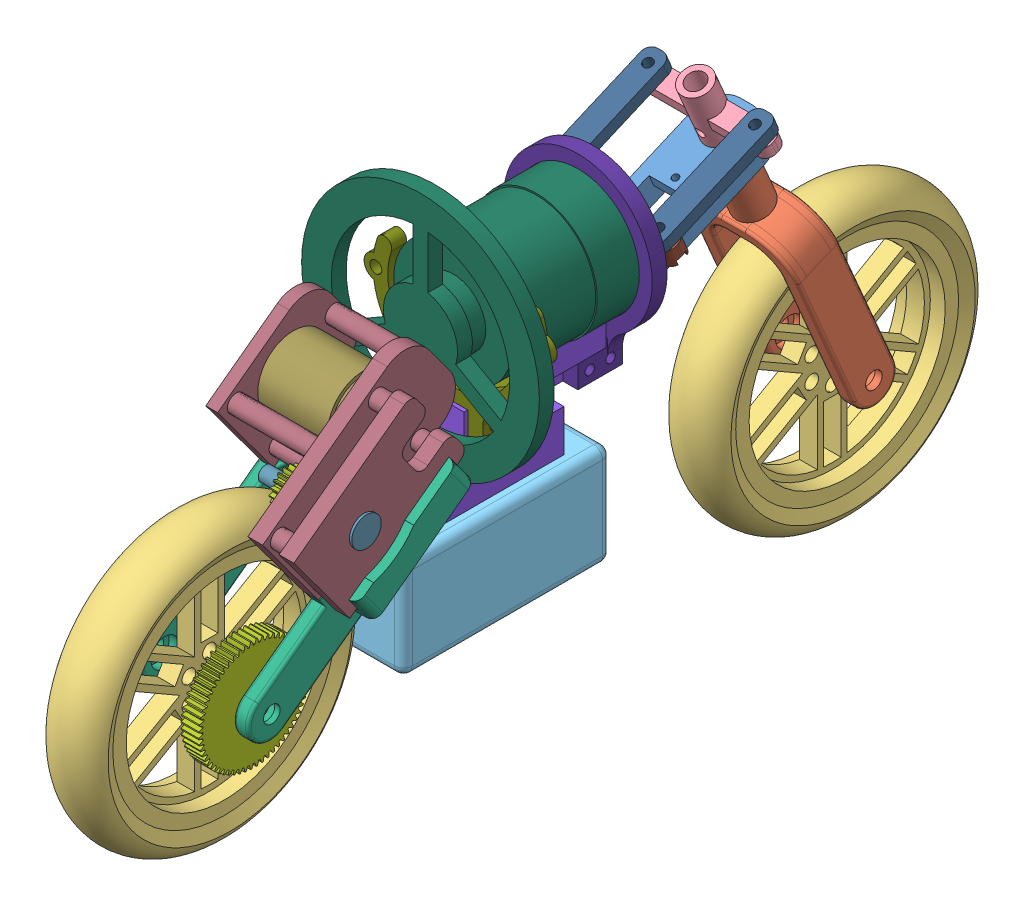
SolidWorks assembly assembly_v5.0, configuration 默认. Lengths in mm.
Overall size (81 161.31 304.62).
23 component instances, 18 part files, 54 mates.
Components (placement in the parent):
- fork_frame-1: fork_frame [默认] at (0 25.2643 106.3234) x (-1 0 0) z (0 0.394535 -0.918881) size (20 18.85 87.51)
- front_fork-1: front_fork [默认] at (0 3.2112 96.8545) x (1 0 0) z (0 -0.394535 0.918881) size (34 88 15)
- tire_v2-1: tire_v2 [默认] at (0 -51.9217 73.1825) x (0 0 -1) z (1 0 0) size (95 95 20)
- tire_v2-2: tire_v2 [默认] at (0 -40.9693 282.7998) x (0 0 -1) z (1 0 0) size (95 95 20)
- steer_link2-1: steer_link2 [默认] at (0 48.2363 116.1868) x (1 0 0) z (0 0.394535 -0.918881) size (45 20 10)
- battery-1: battery [默认] at (0 -50 190) x (0 0 1) z (-1 0 0) size (70 34 21)
- rear_fork_shift-1: rear_fork_shift [默认] at (0 -5.3014 234.5525) x (1 0 0) z (0 0.804121 0.594465) size (58 88.86 58.29)
- spur gear_gb-3: spur gear_gb [GB - Spur gear 0.6M 60T 20PA 6FW ---S60A75H50L5.0N] at (12 -40.9693 282.7998) size (6 37.17 37.17)
- main_body_v2-1: main_body_v2 [默认] at (0 -8.1106 154.2837) x (-1 0 0) z (0 0 -1) size (25 41 79.25)
- PCB-1: PCB [默认] at (-15 -40 189.1936) x (0 -1 0) z (0 0 -1) size (40 4 80)
- steer_link1-1: steer_link1 [默认] at (18 33.0029 128.8542) x (0 0.394535 -0.918881) z (1 0 0) size (44.22 4 7.76)
- steer_link1-2: steer_link1 [默认] at (-18 33.0029 128.8542) x (0 -0.394535 0.918881) z (-1 0 0) size (44.22 4 7.76)
- steer_link0-1: steer_link0 [默认] at (0 27.8147 140.9375) x (-1 0 0) z (0 -0.394535 0.918881) size (45 6 6.84)
- motor_assembly-1: motor_assembly [默认] at (-14.5712 50.6661 212.2557) x (1 0 0) z (0 -0.594465 0.804121) size (49.3 33.1 62.2)
  - motor-1: motor [默认] at (9.0712 0 42) x (1 0 0) z (0 -1 0) size (42 24 24)
  - motor_frame-1: motor_frame [默认] at (42.0712 0 53.1) x (-1 0 0) z (0 0 -1) size (47.5 33.1 62.2)
  - coupling-1: coupling [默认] at (48.3712 0 66.5) x (-1 0 0) z (0 -0.924225 -0.381849) size (34 10.2 13.1)
- 零件3^assembly_v5.0-1: 零件3^assembly_v5.0 [默认] at origin (virtual)
- spur gear_gb-4: spur gear_gb [GB - Spur gear 0.6M 18T 20PA 6FW ---S18A75H50L5.0N] at (12 11.1341 265.7298) size (6 11.87 12)
- flywheel-2: flywheel [默认] at (0 21.8894 149.7837) size (80 80 59)
  - flywheel-1: flywheel [默认] at origin size (80 80 59)
  - flywheel_holder1-1: flywheel_holder1 [默认] at (0 0 48) x (1 0 0) z (0 1 0) size (60 15 44.31)
  - flywheel_holder2-1: flywheel_holder2 [默认] at (0 0 1) x (-1 0 0) z (0 1 0) size (50 15 58.81)
Mates (geometry in assembly coordinates):
- 重合1: coincident: plane of ? through (0 -31.075 159.9884) normal (1 0 0); plane of assembly through (0 0 0) normal (1 0 0)
- 同心1: concentric: circle of ?; circle of ?
- 重合3: coincident anti-aligned: plane of fork_frame-1 through (0 25.2643 106.3234) normal (-1 0 0); plane of assembly through (0 0 0) normal (1 0 0)
- 重合6: coincident: plane of ? through (0 -10.6832 225.7266) normal (1 0 0); plane of assembly through (0 0 0) normal (1 0 0)
- 同心7: concentric aligned: circle of fork_frame-1; circle of front_fork-1
- 同心4: concentric: circle of ?; circle of ?
- 平行2: parallel: plane of ? through (6.7769 -3.6263 174.0749) normal (0 0.707107 -0.707107); plane of ? through (12.5 31.7396 211.9059) normal (0 0.707107 -0.707107)
- 重合10: coincident aligned: plane of tire_v2-1 through (0 -51.9217 73.1825) normal (1 0 0); plane of assembly through (0 0 0) normal (1 0 0)
- 重合11: coincident aligned: plane of tire_v2-2 through (0 -40.9693 282.7998) normal (1 0 0); plane of assembly through (0 0 0) normal (1 0 0)
- 同心5: concentric aligned: cylinder of front_fork-1 through (-17 -51.9217 73.1825) axis (1 0 0) radius 2.8; circle of tire_v2-1
- 重合12: coincident: plane of ? through (0 -89.4964 180.4884) normal (1 0 0); plane of assembly through (0 0 0) normal (1 0 0)
- 重合13: coincident: plane of ? through (0 -89.4964 134.9884) normal (1 0 0); plane of assembly through (0 0 0) normal (1 0 0)
- 重合14: coincident: circle of ?; circle of ?
- 重合15: coincident: circle of ?; circle of ?
- 重合16: coincident anti-aligned: plane of fork_frame-1 through (-10 -0.1106 155.2837) normal (0 -0.918881 -0.394535); plane of front_fork-1 through (0 21.5888 104.7452) normal (0 0.918881 0.394535)
- 重合17: coincident anti-aligned: plane of fork_frame-1 through (-10 10.0309 154.4756) normal (0 0.918881 0.394535); plane of steer_handle-1 through (0 29.8587 108.2961) normal (0 -0.918881 -0.394535)
- 同心8: concentric anti-aligned: circle of steer_link2-1; circle of front_fork-1
- 重合21: coincident aligned: plane of rear_fork_shift-1 through (0 -5.3014 234.5525) normal (1 0 0); plane of assembly through (0 0 0) normal (1 0 0)
- 同心9: concentric aligned: circle of tire_v2-2; circle of rear_fork_shift-1
- 距离3: distance = 10 mm: plane of ? through (10 -51.9137 267.9884) normal (1 0 0); plane of assembly through (0 0 0) normal (1 0 0)
- 同心11: concentric aligned: circle of tire_v2-2; circle of spur gear_gb-3
- 距离4: distance = 12 mm aligned: plane of spur gear_gb-3 through (12 -40.9693 282.7998) normal (1 0 0); plane of assembly through (0 0 0) normal (1 0 0)
- 平行6: parallel anti-aligned: plane of main_body_v2-1 through (0 -8.1106 154.2837) normal (0 0 -1); plane of assembly through (0 0 0) normal (0 0 1)
- 平行7: parallel aligned: plane of main_body_v2-1 through (0 -8.1106 154.2837) normal (0 1 0); plane of assembly through (0 0 0) normal (0 1 0)
- 同心16: concentric aligned: circle of fork_frame-1; circle of PCB_holder-1
- 重合39: coincident anti-aligned: plane of main_body_v2-1 through (0 -8.1106 154.2837) normal (-1 0 0); plane of assembly through (0 0 0) normal (1 0 0)
- 同心19: concentric aligned: cylinder of steer_handle-1 through (18 48.2363 116.1868) axis (0 -0.918881 -0.394535) radius 1.6; cylinder of steer_lever-1 through (18 43.6419 114.2141) axis (0 -0.918881 -0.394535) radius 1.6
- 重合45: coincident anti-aligned: plane of steer_handle-1 through (22.5 41.3473 109.4199) normal (0 0.918881 0.394535); plane of steer_lever-1 through (18 33.0029 128.8542) normal (0 -0.918881 -0.394535)
- 同心20: concentric aligned: cylinder of steer_handle-1 through (-18 48.2363 116.1868) axis (0 -0.918881 -0.394535) radius 1.6; cylinder of steer_lever-2 through (-18 43.6419 114.2141) axis (0 -0.918881 -0.394535) radius 1.6
- 重合50: coincident anti-aligned: plane of steer_handle-1 through (22.5 41.3473 109.4199) normal (0 0.918881 0.394535); plane of steer_lever-2 through (-18 33.0029 128.8542) normal (0 -0.918881 -0.394535)
- 同心22: concentric anti-aligned: cylinder of steer_lever-1 through (18 29.7149 146.6506) axis (0 -0.918881 -0.394535) radius 1.6; cylinder of steer_holder-1 through (18 20.5261 142.7052) axis (0 0.918881 0.394535) radius 1.6
- 重合51: coincident anti-aligned: plane of steer_lever-1 through (18 33.0029 128.8542) normal (0 -0.918881 -0.394535); plane of steer_holder-1 through (0 27.8147 140.9375) normal (0 0.918881 0.394535)
- 重合52: coincident anti-aligned: plane of steer_lever-1 through (18 33.0029 128.8542) normal (0 -0.918881 -0.394535); plane of steer_holder-1 through (0 27.8147 140.9375) normal (0 0.918881 0.394535)
- 同心24: concentric anti-aligned: cylinder of steer_lever-2 through (-18 29.7149 146.6506) axis (0 -0.918881 -0.394535) radius 1.6; cylinder of steer_holder-1 through (-18 20.5261 142.7052) axis (0 0.918881 0.394535) radius 1.6
- 重合53: coincident anti-aligned: plane of steer_lever-2 through (-18 33.0029 128.8542) normal (0 -0.918881 -0.394535); plane of steer_holder-1 through (0 27.8147 140.9375) normal (0 0.918881 0.394535)
- 重合54: coincident: line of steer_holder-1 through (0 20.2504 142.5869) axis (0 0.918881 0.394535)
- 同心25: concentric anti-aligned: circle of rear_fork_shift-1; circle of main_body-1
- 同心26: concentric anti-aligned: circle of rear_fork_shift-1; circle of main_body-1
- 平行10: parallel aligned: plane of tire_v2-1 through (0 -51.9217 73.1825) normal (0 1 0)
- 平行11: parallel aligned: plane of tire_v2-2 through (0 -40.9693 282.7998) normal (0 1 0)
- 重合59: coincident anti-aligned: circle of rear_fork_shift-1; circle of motor_assembly-1/motor_frame-1
- 重合60: coincident anti-aligned: circle of rear_fork_shift-1; circle of motor_assembly-1/motor_frame-1
- 同心28: concentric anti-aligned: circle of motor_assembly-1/coupling-1; circle of spur gear_gb-4
- 重合61: coincident aligned: plane of spur gear_gb-3 through (18 -40.9693 282.7998) normal (1 0 0); plane of spur gear_gb-4 through (18 11.1341 265.7298) normal (1 0 0)
- 重合62: coincident aligned: circle of fork_frame-1; circle of main_body-1
- 重合66: coincident aligned: plane of flywheel-2 through (0 21.8894 149.7837) normal (1 0 0)
- 同心29: concentric aligned: circle of flywheel-2/flywheel_holder1-1; circle of main_body_v2-1
- 重合68: coincident anti-aligned: plane of main_body_v2-1 through (0 -8.1106 154.2837) normal (-1 0 0)
- 平行12: parallel aligned: plane of flywheel-2 through (0 21.8894 149.7837) normal (0 1 0)
- 距离5: distance = 15 mm anti-aligned: plane of PCB-1 through (-15 -40 189.1936) normal (-1 0 0)
- 距离6: distance = 40 mm: plane of assembly through (0 0 0) normal (0 1 0); plane of PCB-1 through (-15 -40 189.1936) normal (0 -1 0)
- 重合72: coincident anti-aligned: plane of battery-1 through (0 -50 190) normal (-1 0 0)
- 距离8: distance = 190 mm aligned: plane of battery-1 through (0 -50 190) normal (0 0 1)
- 距离9: distance = 50 mm aligned: plane of battery-1 through (0 -50 190) normal (0 1 0)
